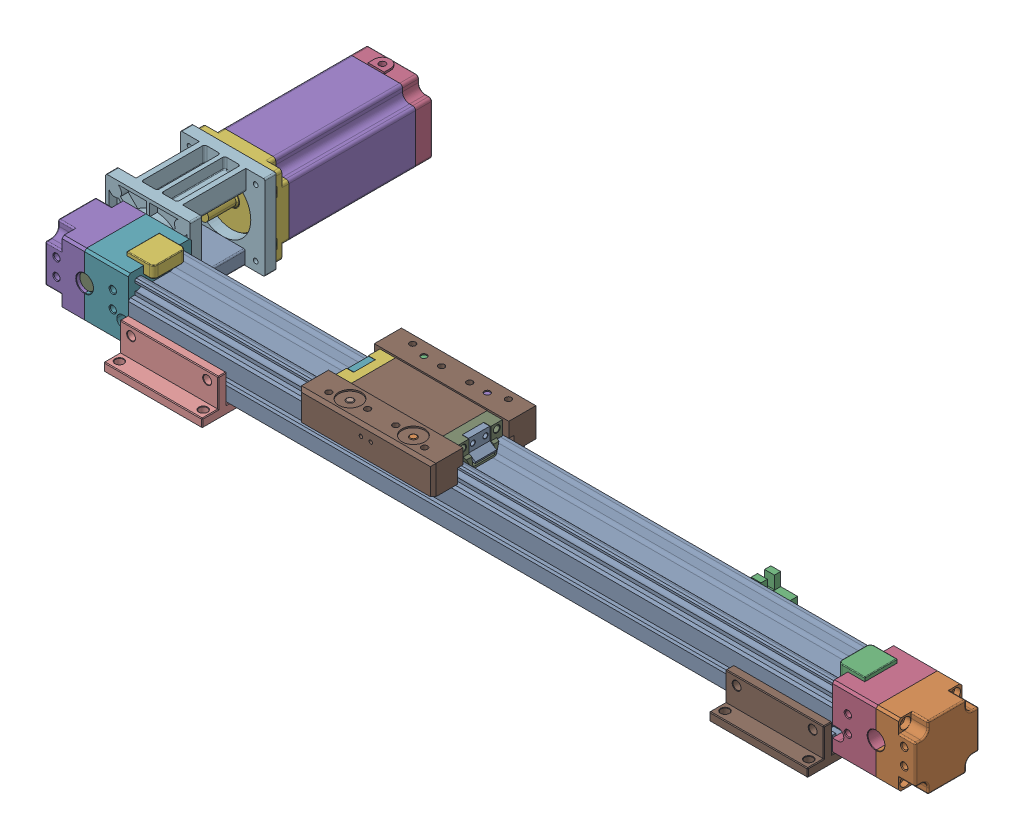
SolidWorks assembly 500_belt_linear_drive, configuration Default. Lengths in mm.
Overall size (620 60 236).
11 component instances, 9 part files, 22 mates.
Components (placement in the parent):
- 500_rail-1: 500_rail [Default] at origin size (500 40 45)
- edge_blacket-1: edge_blacket [Default] at (361.2729 -0.2431 0) size (66 47.7 45)
- motor_blacket-1: motor_blacket [Default] at (-61.2729 -0.2431 0) x (-1 0 0) z (0 0 -1) size (66 47.7 45)
- motor_coupler-1: motor_coupler [Default] at (-127.3892 22.0794 -53) x (1 0 0) z (0 0 -1) size (60 60 61)
- motor-1: motor [Default] at (-131 5.2924 -91.3676) x (0 0 1) z (-1 0 0) size (134.5 57.3 56.3)
- motor_rod-1: motor_rod [Default] at (-131 23.2 -54.65) size (12 12 75)
- under_blacket-1: under_blacket [Default] at (-65 -6.8 0) size (70 26 80)
- under_blacket-2: under_blacket [Default] at (365 -6.8 0) size (70 26 80)
- stage-1: stage [Default] at (91.9558 30.309 0.15) size (95.8 34.5 77)
- side_blacket-1: side_blacket [Default] at (308.0963 7.2 -22.5) x (-1 0 0) z (0 0 -1) size (41.26 18.31 23.59)
- side_blacket-2: side_blacket [Default] at (114.3192 7.2 -22.5) x (-1 0 0) z (0 0 -1) size (41.26 18.31 23.59)
Mates (geometry in assembly coordinates):
- 일치1: coincident anti-aligned: plane of 400_rail-1 through (400 0 0) normal (1 0 0); plane of edge_blacket-1 through (400 21.7 0) normal (-1 0 0)
- 동심1: concentric aligned: cylinder of 400_rail-1 through (400 26 0) axis (1 0 0) radius 2.1; cylinder of edge_blacket-1 through (400 26 0) axis (1 0 0) radius 2.7
- 일치2: coincident anti-aligned: plane of 400_rail-1 through (-100 0 0) normal (-1 0 0); plane of motor_blacket-1 through (-100 21.7 0) normal (1 0 0)
- 동심2: concentric anti-aligned: cylinder of 400_rail-1 through (400 26 0) axis (1 0 0) radius 2.1; cylinder of motor_blacket-1 through (-100 26 0) axis (-1 0 0) radius 2.7
- 일치3: coincident anti-aligned: plane of motor_blacket-1 through (-159 -0.8 -22.5) normal (0 0 -1); plane of motor_coupler-1 through (-131 23.2 -22.5) normal (0 0 1)
- 동심3: concentric aligned: cylinder of motor_blacket-1 through (-131 23.2 22.5) axis (0 0 1) radius 6; cylinder of motor_coupler-1 through (-131 23.2 -83.5) axis (0 0 1) radius 16.5
- 동심4: concentric aligned: cylinder of motor_blacket-1 through (-131 23.2 22.5) axis (0 0 1) radius 6; cylinder of motor_rod-1 through (-131 23.2 -54.65) axis (0 0 1) radius 6
- 일치4: distance = 2.15 mm aligned: plane of motor_rod-1 through (-131 23.2 20.35) normal (0 0 1); plane of motor_blacket-1 through (-159 44.2 22.5) normal (0 0 1)
- 동심5: concentric aligned: cylinder of motor_coupler-1 through (-154.5 46.7 -83.5) axis (0 0 -1) radius 1.65; cylinder of motor-1 through (-154.5 46.7 -83.5) axis (0 0 -1) radius 2.6
- 일치5: coincident anti-aligned: plane of motor_coupler-1 through (-131 23.2 -83.5) normal (0 0 -1); plane of motor-1 through (-131 23.2 -83.5) normal (0 0 1)
- 일치6: coincident anti-aligned: plane of 400_rail-1 through (-100 -0.8 17.85) normal (0 -1 0); plane of under_blacket-1 through (-100 -0.8 22.5) normal (0 1 0)
- 일치7: coincident anti-aligned: plane of 400_rail-1 through (0 0 22.5) normal (0 0 1); plane of under_blacket-1 through (-100 19.2 22.5) normal (0 0 -1)
- 일치8: coincident anti-aligned: plane of 400_rail-1 through (-100 -0.8 17.85) normal (0 -1 0); plane of under_blacket-2 through (330 -0.8 22.5) normal (0 1 0)
- 일치9: coincident anti-aligned: plane of 400_rail-1 through (0 0 22.5) normal (0 0 1); plane of under_blacket-2 through (330 19.2 22.5) normal (0 0 -1)
- 일치10: coincident aligned: plane of 400_rail-1 through (400 0 0) normal (1 0 0); plane of under_blacket-2 through (400 -6.8 40) normal (1 0 0)
- 일치11: coincident aligned: plane of 400_rail-1 through (-100 0 0) normal (-1 0 0); plane of under_blacket-1 through (-100 -6.8 -40) normal (-1 0 0)
- 일치12: distance = 18.2 mm aligned: plane of stage-1 through (83.8693 49.4 0.15) normal (0 1 0); plane of 400_rail-1 through (400 31.2 -9.1195) normal (0 1 0)
- 탄젠트1: tangent anti-aligned: plane of 400_rail-1 through (400 36.7055 -17.85) normal (0 0 -1); cylinder of stage-1 through (106.3693 29.7 -26.1) axis (0 -1 0) radius 8.25
- 일치13: coincident anti-aligned: plane of 400_rail-1 through (-100 -0.8 -22.5) normal (0 0 -1); plane of side_blacket-1 through (280.8205 7.2 -22.5) normal (0 0 1)
- 일치14: distance = 8 mm aligned: plane of side_blacket-1 through (308.0963 7.2 -22.5) normal (0 -1 0); plane of 400_rail-1 through (-100 -0.8 17.85) normal (0 -1 0)
- 일치15: coincident anti-aligned: plane of 400_rail-1 through (-100 -0.8 -22.5) normal (0 0 -1); plane of side_blacket-2 through (87.0434 7.2 -22.5) normal (0 0 1)
- 일치16: distance = 8 mm aligned: plane of side_blacket-2 through (114.3192 7.2 -22.5) normal (0 -1 0); plane of 400_rail-1 through (-100 -0.8 17.85) normal (0 -1 0)
